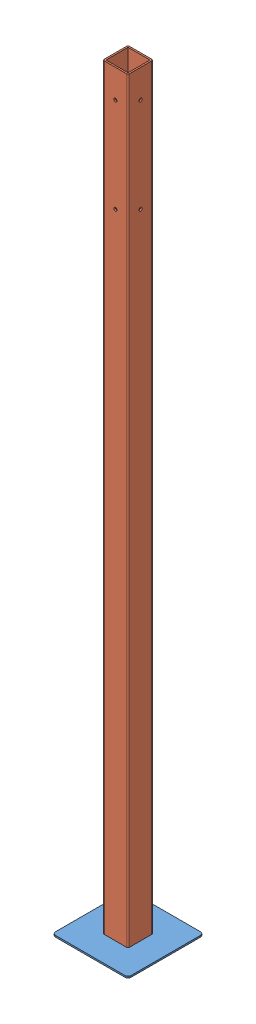
SolidWorks assembly upright assy, configuration Default. Lengths in mm.
Overall size (304.8 3054.35 304.8).
2 component instances, 2 part files, 3 mates.
Components (placement in the parent):
- base plate-1: base plate [Default] at origin size (304.8 6.35 304.8)
- upright-1: upright [Default] at (0 1530.35 0) size (101.6 3048 101.6)
Mates (geometry in assembly coordinates):
- Coincident1: coincident anti-aligned: plane of base plate-1 through (-139.7 6.35 139.7) normal (0 1 0); plane of upright-1 through (-44.45 6.35 44.45) normal (0 -1 0)
- Coincident2: coincident aligned: plane of upright-1 through (0 1530.35 0) normal (1 0 0); plane of assembly through (0 0 0) normal (1 0 0)
- Coincident3: coincident aligned: plane of upright-1 through (0 1530.35 0) normal (0 0 1); plane of assembly through (0 0 0) normal (0 0 1)
